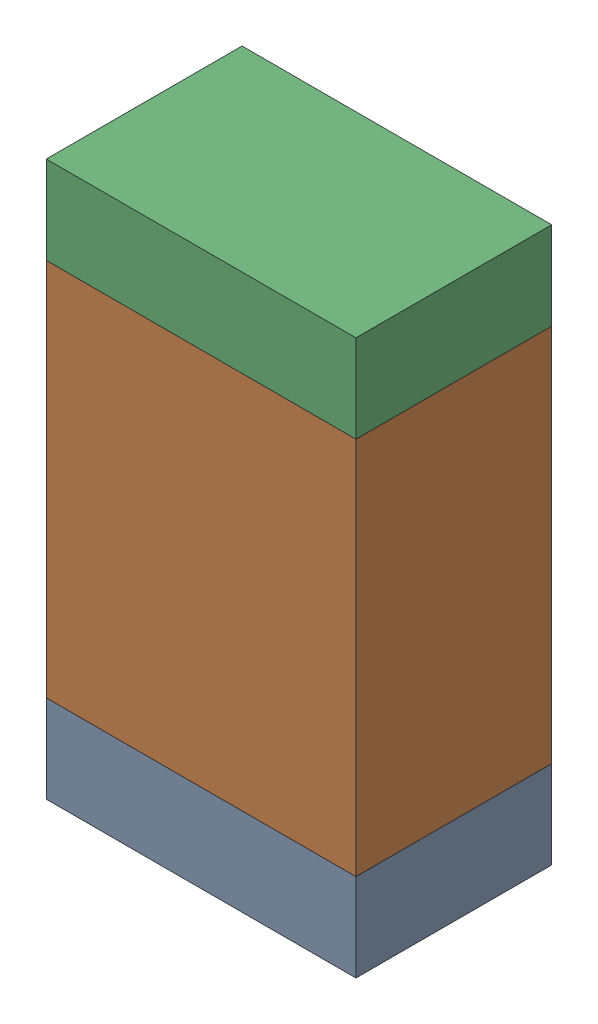
SolidWorks assembly R04-2, configuration Default. Lengths in mm.
Overall size (0.95 1.7 0.6).
6 component instances, 2 part files, 0 mates.
Components (placement in the parent):
- 959206216-2-1: 959206216-2 [Default] at (141.478 81.581 0) size (0.95 0.27 0.6)
  - Extruded-62-1: Extruded-62 [Default] at origin size (0.95 0.27 0.6)
- 959206352-2-1: 959206352-2 [Default] at (141.478 82.296 0) size (0.95 1.16 0.6)
  - Extruded-63-1: Extruded-63 [Default] at origin size (0.95 1.16 0.6)
- 959206216-2-2: 959206216-2 [Default] at (141.478 83.011 0) size (0.95 0.27 0.6)
  - Extruded-62-1: Extruded-62 [Default] at origin size (0.95 0.27 0.6)
